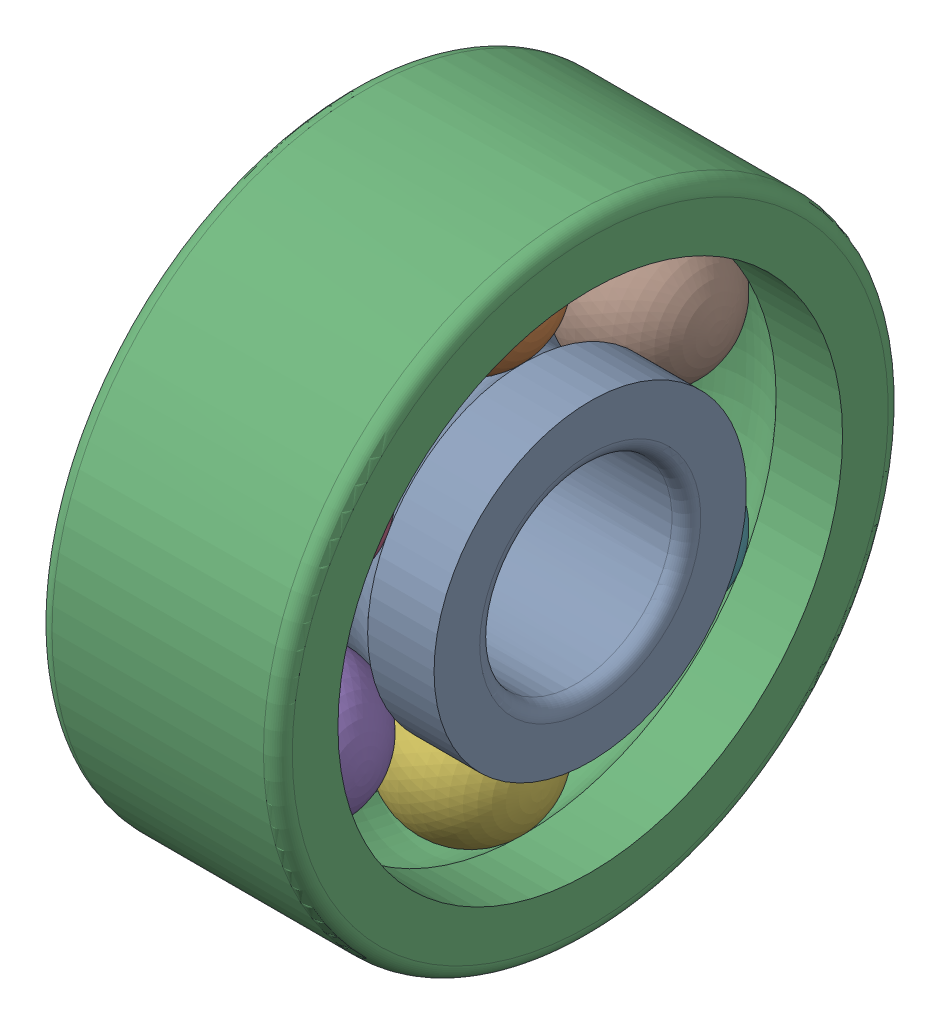
SolidWorks assembly Roul-bille-1-moteur-, configuration Défaut. Lengths in mm.
Overall size (5 13 13).
8 component instances, 3 part files, 12 mates.
Components (placement in the parent):
- bague-int-moteur-1-1: bague-int-moteur-1 [Défaut] at origin size (5 6.5 6.5)
- Bille-moteur-1-1: Bille-moteur-1 [Défaut] at origin size (3 3 3)
- bague-ext-moteur-1-1: bague-ext-moteur-1 [Défaut] at origin size (5 13 13)
- Bille-moteur-1-2: Bille-moteur-1 [Défaut] x (1 0 0) z (0 -0.866025 0.5) size (3 3 3)
- Bille-moteur-1-3: Bille-moteur-1 [Défaut] x (1 0 0) z (0 -0.866025 -0.5) size (3 3 3)
- Bille-moteur-1-4: Bille-moteur-1 [Défaut] x (1 0 0) z (0 0 -1) size (3 3 3)
- Bille-moteur-1-5: Bille-moteur-1 [Défaut] x (1 0 0) z (0 0.866025 -0.5) size (3 3 3)
- Bille-moteur-1-6: Bille-moteur-1 [Défaut] x (1 0 0) z (0 0.866025 0.5) size (3 3 3)
Mates (geometry in assembly coordinates):
- Sur place1: in place: plane of ?; moOrthogonalPlaneRef_w of ? through (-1000 0 0) axis (0 0 1); line of ? through (1000 -1000 0) axis (0 0 1); unknown of ?
- Coïncidente1: coincident aligned: plane of bague-int-moteur-1-1; plane of assembly
- Coïncidente2: coincident aligned: plane of ? through (0 0 0) normal (0 1 0)
- Coïncidente3: coincident anti-aligned: plane of ? through (0 0 0) normal (1 0 0)
- Sur place2: in place: line of ? through (0 0 0) axis (0 0 1); line of ? through (-1000 0 0) axis (0 0 1); line of ? through (1000 -1000 0) axis (0 0 1); unknown of ?
- Coïncidente4: coincident aligned: plane of Bille-moteur-1-1; plane of assembly
- Coïncidente5: coincident aligned: plane of ? through (0 0 0) normal (0 1 0)
- Coïncidente6: coincident anti-aligned: plane of ? through (0 0 0) normal (1 0 0)
- Sur place3: in place: line of ? through (0 0 0) axis (0 0 1); line of ? through (-1000 0 0) axis (0 0 1); line of ? through (1000 -1000 0) axis (0 0 1); unknown of ?
- Coïncidente7: coincident aligned: plane of bague-ext-moteur-1-1; plane of assembly
- Coïncidente8: coincident aligned: plane of ? through (0 0 0) normal (0 1 0)
- Coïncidente9: coincident anti-aligned: plane of ? through (0 0 0) normal (1 0 0)
